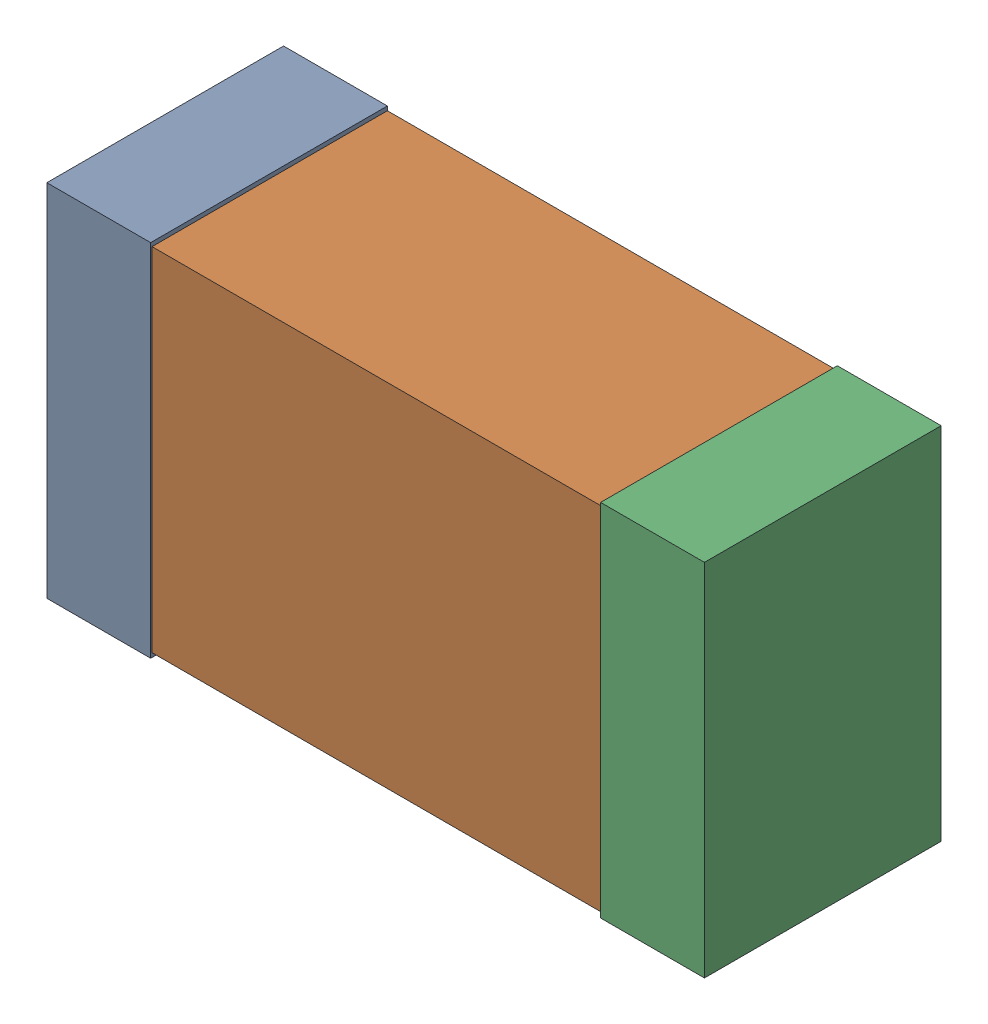
SolidWorks assembly C14_Motor_11Kanaloa_v2.0.0_Motor, configuration Default. Lengths in mm.
Overall size (2.38 1.3 0.85).
6 component instances, 2 part files, 0 mates.
Components (placement in the parent):
- 352877648-1: 352877648 [Default] at (119.412 166.624 0) size (0.38 1.3 0.85)
  - Extruded_14-1: Extruded_14 [Default] at origin size (0.38 1.3 0.85)
- 352877392-1: 352877392 [Default] at (120.412 166.624 0) size (2.2 1.27 0.85)
  - Extruded_15-1: Extruded_15 [Default] at origin size (2.2 1.27 0.85)
- 352877648-2: 352877648 [Default] at (121.412 166.624 0) size (0.38 1.3 0.85)
  - Extruded_14-1: Extruded_14 [Default] at origin size (0.38 1.3 0.85)
